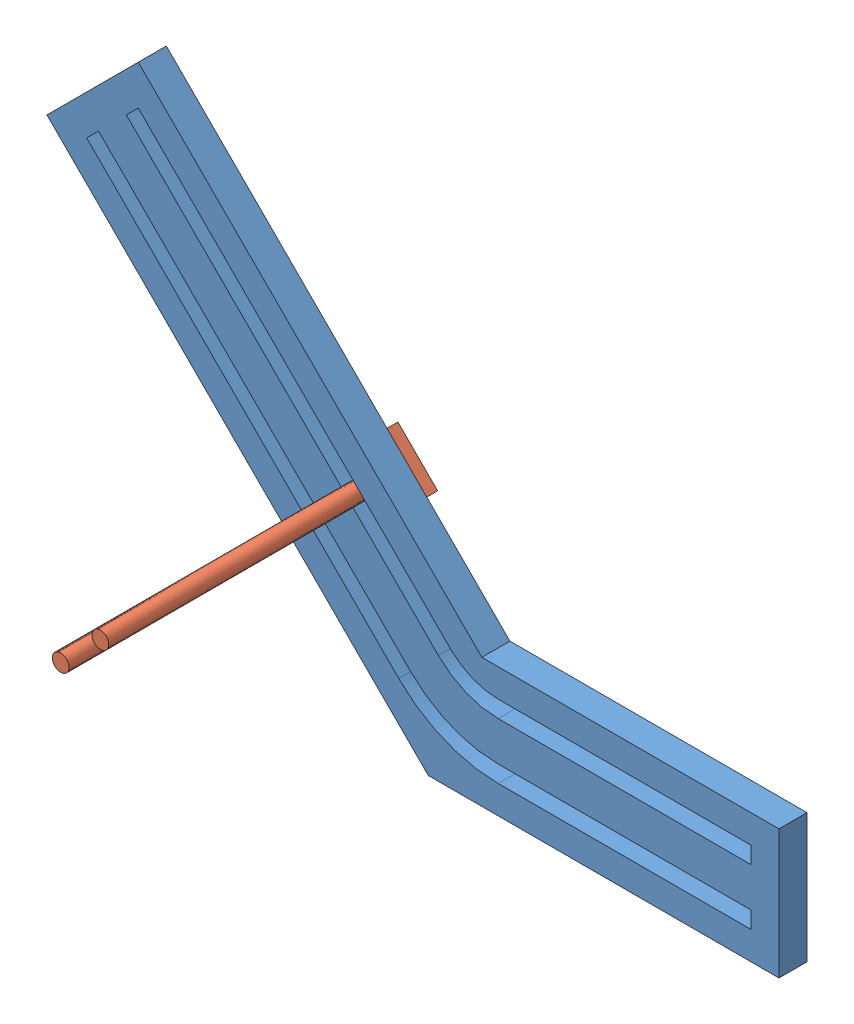
SolidWorks assembly path_test, configuration Default. Lengths in mm.
Overall size (130.38 84.19 58).
2 component instances, 2 part files, 2 mates.
Components (placement in the parent):
- travel_path2-1: travel_path2 [Default] at (48.722 44.0454 116.3565) size (130.38 84.19 5)
- slider_crank2-1: slider_crank2 [Default] at (25.5589 62.2586 113.3565) x (-0.707107 -0.707107 0) z (-0.707107 0.707107 0) size (20 58 10)
Mates (geometry in assembly coordinates):
- Coincident1: coincident anti-aligned: plane of travel_path2-1 through (48.722 44.0454 116.3565) normal (0 0 -1); plane of slider_crank2-1 through (32.5832 55.2344 116.3565) normal (0 0 1)
- PathMate4: path: unknown of ?; edge_curve of travel_path2-1
